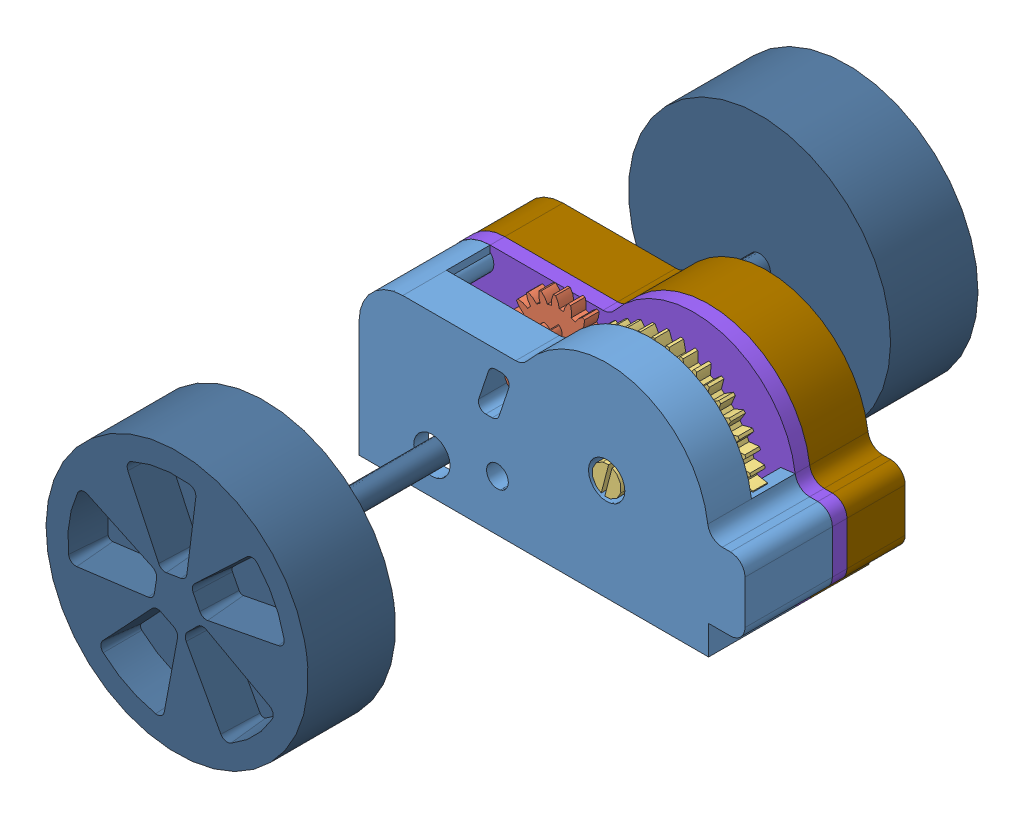
SolidWorks assembly Assem3, configuration Default. Lengths in mm.
Overall size (31.81 22.86 46).
10 component instances, 10 part files, 26 mates.
Components (placement in the parent):
- body1-1: body1 [Default] at (12.0559 14.1105 19.0078) size (26.5 14 9)
- lower_small_gear-1: lower_small_gear [Metric - Spur gear 0.3M 10T 20PA 1FW ---S10N75H50L0.8N] at (4.3059 15.4105 21.5078) x (0 0 -1) z (0.022661 -0.999743 0) size (5 6.87 6.89)
- lower.large.gear-1: lower.large.gear [Metric - Spur gear 0.3M 18T 20PA 5FW ---S18N75H50L0.8N] at (12.0559 14.1105 15.5078) x (0 0 1) z (-0.251662 -0.967815 0) size (11 13.18 13.2)
- spring-1: spring [Default] at (12.0559 14.1105 23.2578) x (0.8623 0.506397 0) z (0 0 -1) size (11.16 11.54 1.51)
- shaft_gear-1: shaft_gear [Metric - Spur gear 0.3M 10T 20PA 3FW ---S10O2.3H8L1.5N] at (0.0559 9.6105 18.5078) x (0 0 -1) z (0.775217 -0.631695 0) size (8 3.45 3.6)
- upper_big_gear-1: upper_big_gear [Metric - Spur gear 0.3M 11T 20PA 2.5FW ---S11N75H50L0.8N] at (4.5559 10.6105 20.0078) x (0 0 -1) z (0.296216 -0.955121 0) size (8.5 5.93 6)
- upper_small_gear-1: upper_small_gear [Metric - Spur gear 0.3M 11T 20PA 2.5FW ---S11O1.5H5L0.8N] at (7.8059 13.6105 15.5078) x (0 0 1) z (0.655161 0.755489 0) size (6 3.83 3.87)
- spacer-1: spacer [Default] at (12.0559 14.1105 18.0078) size (26.5 14 1)
- body2-1: body2 [Default] at (12.0559 14.1105 14.0078) size (26.5 14 4)
- wheel-1: wheel [Default] at (0.0559 9.6105 36.5078) x (0.987389 0.15831 0) z (0 0 1) size (18 18 46)
Mates (geometry in assembly coordinates):
- Concentric1: concentric aligned: cylinder of body1-1 through (12.0559 14.1105 25.0078) axis (0 0 -1) radius 1.25; circle of spring-1
- Coincident3: coincident anti-aligned: plane of body1-1 through (-1.9441 15.1105 24.0078) normal (0 0 -1); plane of spring-1 through (10.2987 8.4347 24.0078) normal (0 0 1)
- Concentric2: concentric aligned: cylinder of body1-1 through (12.0559 14.1105 25.0078) axis (0 0 -1) radius 1.25; cylinder of lower.large.gear-1 through (12.0559 14.1105 25.0078) axis (0 0 -1) radius 1
- Coincident4: coincident aligned: plane of body1-1 through (-1.9441 15.1105 25.0078) normal (0 0 1); plane of lower.large.gear-1 through (12.0559 14.1105 25.0078) normal (0 0 1)
- Concentric3: concentric aligned: circle of body1-1; cylinder of lower_small_gear-1 through (4.3059 15.4105 23.5078) axis (0 0 -1) radius 0.75
- Coincident6: coincident anti-aligned: plane of lower_small_gear-1 through (5.1277 14.1796 20.5078) normal (0 0 1); plane of lower.large.gear-1 through (10.3107 11.7198 20.5078) normal (0 0 -1)
- Coincident7: coincident aligned: plane of body1-1 through (21.5559 13.1105 25.0078) normal (1 0 0); plane of spacer-1 through (21.5559 13.1105 19.0078) normal (1 0 0)
- Coincident8: coincident aligned: plane of body1-1 through (19.0559 7.1105 25.0078) normal (0 -1 0); plane of spacer-1 through (19.0559 7.1105 19.0078) normal (0 -1 0)
- Coincident9: coincident anti-aligned: plane of body1-1 through (-1.9441 15.1105 19.0078) normal (0 0 -1); plane of spacer-1 through (-1.9441 15.1105 19.0078) normal (0 0 1)
- Coincident10: coincident aligned: plane of body1-1 through (21.5559 13.1105 25.0078) normal (1 0 0); plane of body2-1 through (21.5559 13.1105 18.0078) normal (1 0 0)
- Coincident11: coincident aligned: plane of body1-1 through (19.0559 7.1105 25.0078) normal (0 -1 0); plane of body2-1 through (19.0559 7.1105 18.0078) normal (0 -1 0)
- Coincident12: coincident anti-aligned: plane of spacer-1 through (-1.9441 15.1105 18.0078) normal (0 0 -1); plane of body2-1 through (-1.9441 15.1105 18.0078) normal (0 0 1)
- Concentric5: concentric aligned: cylinder of upper_small_gear-1 through (7.8059 13.6105 19.0078) axis (0 0 -1) radius 0.75; circle of body2-1
- Coincident13: coincident aligned: plane of lower.large.gear-1 through (12.0559 14.1105 15.5078) normal (0 0 -1); plane of upper_small_gear-1 through (7.8059 13.6105 15.5078) normal (0 0 -1)
- Concentric7: concentric anti-aligned: cylinder of upper_big_gear-1 through (4.5559 10.6105 22.5078) axis (0 0 -1) radius 0.75; cylinder of body2-1 through (4.5559 10.6105 14.0078) axis (0 0 1) radius 1
- Coincident14: coincident aligned: plane of upper_big_gear-1 through (5.7876 10.3066 15.5078) normal (0 0 -1); plane of upper_small_gear-1 through (7.8059 13.6105 15.5078) normal (0 0 -1)
- Concentric8: concentric aligned: cylinder of shaft_gear-1 through (0.0559 9.6105 15.5078) axis (0 0 1) radius 1.124; cylinder of body2-1 through (0.0559 9.6105 14.0078) axis (0 0 1) radius 1.25
- Coincident15: coincident aligned: plane of shaft_gear-1 through (0.0559 9.6105 15.5078) normal (0 0 -1); plane of upper_big_gear-1 through (5.7876 10.3066 15.5078) normal (0 0 -1)
- Concentric9: concentric aligned: cylinder of shaft_gear-1 through (0.0559 9.6105 10.5078) axis (0 0 1) radius 0.75; cylinder of wheel-1 through (0.0559 9.6105 19.5078) axis (0 0 1) radius 0.75
- Width1: width anti-aligned: plane of wheel-1 through (0.0559 9.6105 2.5078) normal (0 0 1); plane of body2-1 through (0.0559 9.6105 36.5078) normal (0 0 -1); plane of wheel-1 through (-1.9441 15.1105 14.0078) normal (0 0 -1); plane of body1-1 through (-1.9441 15.1105 25.0078) normal (0 0 1)
- GearMate1: gear = 1.5 : 1.5 mm: cylinder of lower.large.gear-1 through (12.0559 14.1105 14.0078) axis (0 0 1) radius 0.75; cylinder of upper_small_gear-1 through (7.8059 13.6105 13.0078) axis (0 0 1) radius 0.75
- GearMate2: gear = 1.5 : 1.5 mm: cylinder of upper_small_gear-1 through (7.8059 13.6105 13.0078) axis (0 0 1) radius 0.75; cylinder of upper_big_gear-1 through (4.5559 10.6105 14.0078) axis (0 0 1) radius 0.75
- GearMate3: gear = 1.5 : 2.248 mm: cylinder of shaft_gear-1 through (0.0559 9.6105 15.5078) axis (0 0 1) radius 1.124; cylinder of upper_big_gear-1 through (4.5559 10.6105 14.0078) axis (0 0 1) radius 0.75
- GearMate4: gear = 2.248 : 1.5 mm: cylinder of wheel-1 through (0.0559 9.6105 19.5078) axis (0 0 1) radius 0.75; cylinder of shaft_gear-1 through (0.0559 9.6105 15.5078) axis (0 0 1) radius 1.124
- GearMate5: gear = 1.5 : 2 mm: cylinder of lower.large.gear-1 through (12.0559 14.1105 25.0078) axis (0 0 -1) radius 1; cylinder of lower_small_gear-1 through (4.3059 15.4105 23.5078) axis (0 0 -1) radius 0.75
- Parallel2: parallel anti-aligned: plane of lower.large.gear-1 through (12.3282 15.6544 23.0078) normal (0.967815 -0.251662 0); plane of spring-1 through (11.6816 12.952 24.0078) normal (-0.967815 0.251662 0)
